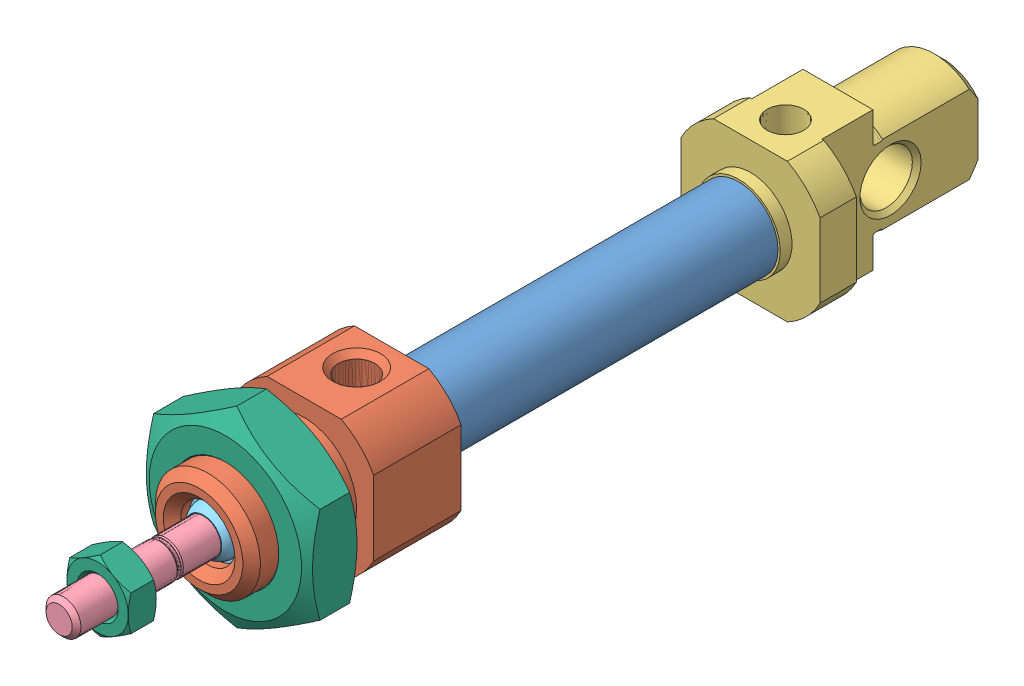
SolidWorks assembly Janatics-Default, configuration Default. Lengths in mm.
Overall size (19 21.94 101).
7 component instances, 6 part files, 17 mates.
Components (placement in the parent):
- Janatics-Default_Cylinder Barrel-1: Janatics-Default_Cylinder Barrel [1501160000] at origin size (9 9 38.3)
- Janatics-Default_Front end cover-1: Janatics-Default_Front end cover [410198] at (0 0 29) size (15.88 15.88 27)
- Janatics-Default_Rear End Cover-1: Janatics-Default_Rear End Cover [410197] at (0 0 -20.5) x (0 0 1) z (-1 0 0) size (27 15.9 15.9)
- Janatics-Default_Piston rod-1: Janatics-Default_Piston rod [101050000] at (0 0 26.5) x (0 0 1) z (0 1 0) size (74 8 8)
- Janatics-Default_Nut ring cum wiper-1: Janatics-Default_Nut ring cum wiper [641529] at (0 0 40.5) x (-0.923121 0.38451 0) z (0.38451 0.923121 0) size (9.1 4.5 9.1)
- Janatics-Default_Lock Nut-1: Janatics-Default_Lock Nut [832001] at (0 0 36.5) x (0 0 -1) z (1 0 0) size (6 21.94 19)
- Janatics-Default_Lock Nut-2: Janatics-Default_Lock Nut [830016] at (0 0 52.5) x (0 0 1) z (-1 0 0) size (3.2 8.08 7)
Mates (geometry in assembly coordinates):
- Concentric1: concentric aligned: cylinder of Janatics-Default_Cylinder Barrel-1 through (0 0 0) axis (0 0 1) radius 4; cylinder of Janatics-Default_Front end cover-1 through (0 0 29) axis (0 0 1) radius 4.1
- Coincident1: coincident aligned: plane of Janatics-Default_Front end cover-1 through (0 0 29) normal (1 0 0)
- Concentric2: concentric anti-aligned: cylinder of Janatics-Default_Cylinder Barrel-1 through (0 0 0) axis (0 0 1) radius 4; cylinder of Janatics-Default_Rear End Cover-1 through (0 0 -20.5) axis (0 0 -1) radius 4.75
- Concentric3: concentric anti-aligned: cylinder of Janatics-Default_Cylinder Barrel-1 through (0 0 0) axis (0 0 1) radius 4; cylinder of Janatics-Default_Piston rod-1 through (0 0 26.5) axis (0 0 -1) radius 2
- Coincident5: coincident anti-aligned: plane of Janatics-Default_Cylinder Barrel-1 through (0 4.5 -19.15) normal (0 0 -1); plane of Janatics-Default_Rear End Cover-1 through (0 4.75 -19.15) normal (0 0 1)
- Coincident6: coincident anti-aligned: circle of Cylinder Barrel-1; plane of Janatics-Default_Front end cover-1 through (0 4.75 19.15) normal (0 0 -1)
- Coincident7: coincident anti-aligned: plane of Janatics-Default_Rear End Cover-1 through (0 3.78 -15.5) normal (0 0 1); plane of Janatics-Default_Piston rod-1 through (0 0 -15.5) normal (0 0 -1)
- Concentric4: concentric aligned: cylinder of Janatics-Default_Piston rod-1 through (0 0 26.5) axis (0 0 -1) radius 2; cylinder of Janatics-Default_Nut ring cum wiper-1 through (0 0 40.5) axis (0 0 -1) radius 1.75
- Coincident8: coincident anti-aligned: plane of Janatics-Default_Front end cover-1 through (0 3.1 40.5) normal (0 0 -1); plane of Janatics-Default_Nut ring cum wiper-1 through (1.5957 3.831 40.5) normal (0 0 1)
- Concentric5: concentric anti-aligned: cylinder of Janatics-Default_Front end cover-1 through (0 0 29) axis (0 0 1) radius 6; cylinder of Janatics-Default_Lock Nut-1 through (0 0 33.5) axis (0 0 -1) radius 5.4
- Width1: width aligned: plane of Janatics-Default_Lock Nut-1 through (0 0 39.5) normal (0 0 1); plane of Janatics-Default_Lock Nut-1 through (0 0 33.5) normal (0 0 -1); plane of Janatics-Default_Front end cover-1 through (0 4.1 42.5) normal (0 0 1); plane of Janatics-Default_Front end cover-1 through (0 6 30.5) normal (0 0 1)
- Concentric6: concentric anti-aligned: cylinder of Janatics-Default_Piston rod-1 through (0 0 26.5) axis (0 0 -1) radius 2; cylinder of Janatics-Default_Lock Nut-2 through (0 0 54.1) axis (0 0 1) radius 1.65
- Width2: width aligned: plane of Janatics-Default_Lock Nut-2 through (0 0 54.1) normal (0 0 1); plane of Janatics-Default_Lock Nut-2 through (0 0 50.9) normal (0 0 -1); plane of Janatics-Default_Piston rod-1 through (1.9464 0 46.5) normal (0 0 1); plane of Janatics-Default_Piston rod-1 through (1.5 0 58.5) normal (0 0 1)
- Coincident9: coincident anti-aligned: plane of Janatics-Default_Rear End Cover-1 through (0 0 -20.5) normal (-1 0 0)
- Coincident10: coincident aligned: plane of Janatics-Default_Lock Nut-1 through (0 0 36.5) normal (1 0 0)
- Coincident11: coincident anti-aligned: plane of Janatics-Default_Lock Nut-2 through (0 0 52.5) normal (-1 0 0)
- Parallel1: parallel aligned: plane of Piston rod-1 through (2.5 1.6583 47.0005) normal (1 0 0); plane of Lock Nut-1 through (12 6.9282 33.5005) normal (1 0 0)
